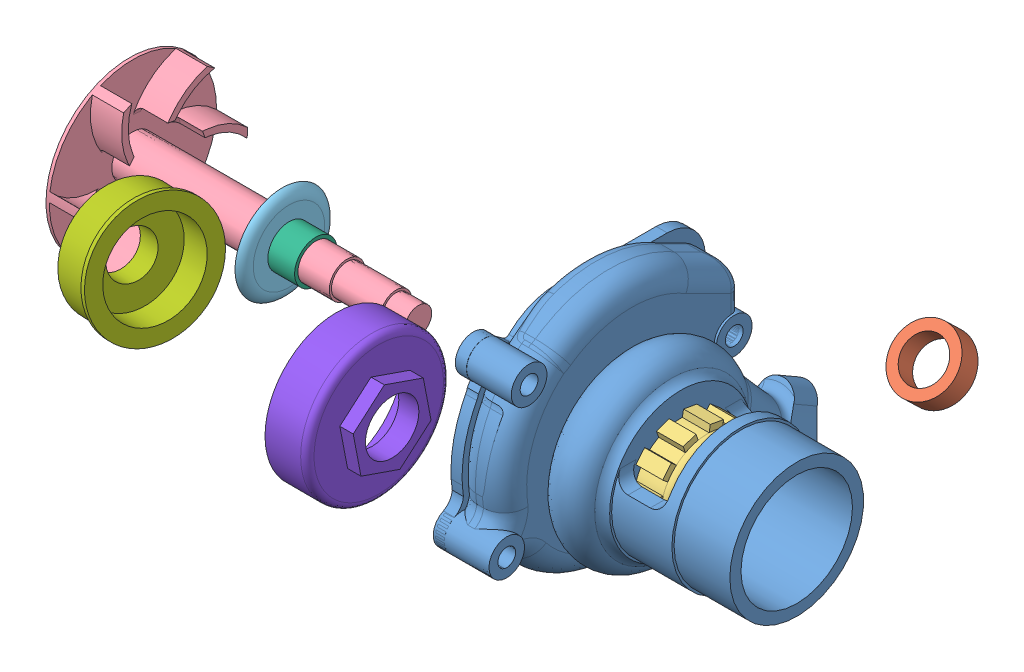
SolidWorks assembly Assem1, configuration Default. Lengths in mm.
Overall size (316.63 170.21 294.1).
9 component instances, 9 part files, 10 mates.
Components (placement in the parent):
- Part1Body-1: Part1Body [Default<As Machined>] at (31.1898 76.0888 110.7889) size (101 118.16 132.43)
- Part3-1: Part3 [Default] at (10.6644 47.7727 -15.7864) x (1 0 0) z (0 -0.694658 -0.71934) size (28 28 10)
- Part4-1: Part4 [Default] at (28.1898 76.0888 110.7889) x (1 0 0) z (0 0.54469 0.838637) size (16 48 48)
- Part5-1: Part5 [Default] at (-217.4387 76.0888 110.7889) x (0 0.996496 0.083639) z (1 0 0) size (75 75 147)
- Part6-1: Part6 [Default] at (-153.9183 76.0888 110.7889) x (1 0 0) z (0 -0.999992 0.004044) size (3 42.38 42.38)
- Part7-1: Part7 [Default] at (-147.4387 76.0888 110.7889) x (0 0.999992 -0.004044) z (1 0 0) size (19 19 12)
- Part8-1: Part8 [Default] at (-99.7737 156.3035 229.4982) x (-0.973846 -0.137832 -0.180627) z (0.158977 -0.981325 -0.10829) size (23 54 54)
- Part9-1: Part9 [Default] at (-7.6018 147.5642 229.3961) size (25 64 64)
- PUMP_part 2-1: PUMP_part 2 [Default] at (14.1898 76.0888 110.7889) x (1 0 0) z (0 0.21295 0.977063) size (54 42 42)
Mates (geometry in assembly coordinates):
- Concentric1: concentric anti-aligned: cylinder of Part1Body-1 through (80.1898 76.0888 110.7889) axis (1 0 0) radius 19; cylinder of PUMP_part 2-1 through (-12.8102 76.0888 110.7889) axis (-1 0 0) radius 19
- Concentric3: concentric anti-aligned: circle of Part1Body-1; cylinder of PUMP_part 2-1 through (-12.8102 76.0888 110.7889) axis (-1 0 0) radius 17.5
- Coincident1: coincident anti-aligned: circle of Part1Body-1; circle of PUMP_part 2-1
- Concentric4: concentric aligned: cylinder of Part4-1 through (40.1898 76.0888 110.7889) axis (-1 0 0) radius 17.5; cylinder of PUMP_part 2-1 through (-12.8102 76.0888 110.7889) axis (-1 0 0) radius 17.5
- Coincident2: coincident aligned: circle of Part4-1; circle of PUMP_part 2-1
- Concentric5: concentric anti-aligned: cylinder of Part5-1 through (-152.6331 76.0888 110.7889) axis (-1 0 0) radius 8; cylinder of Part6-1 through (-178.6331 76.0888 110.7889) axis (1 0 0) radius 7.9951
- Concentric6: concentric aligned: cylinder of Part5-1 through (-152.6331 76.0888 110.7889) axis (-1 0 0) radius 8; cylinder of Part7-1 through (-166.6331 76.0888 110.7889) axis (-1 0 0) radius 8
- Coincident3: coincident anti-aligned: plane of Part5-1 through (-180.6331 76.0888 110.7889) normal (1 0 0); plane of Part6-1 through (-180.6331 76.0888 110.7889) normal (-1 0 0)
- Coincident4: coincident anti-aligned: plane of Part6-1 through (-178.6331 76.0888 110.7889) normal (1 0 0); plane of Part7-1 through (-178.6331 76.0888 110.7889) normal (-1 0 0)
- Concentric8: concentric aligned: cylinder of Part5-1 through (37.5027 76.0888 110.7889) axis (-1 0 0) radius 9.5; cylinder of PUMP_part 2-1 through (-12.8102 76.0888 110.7889) axis (-1 0 0) radius 10
